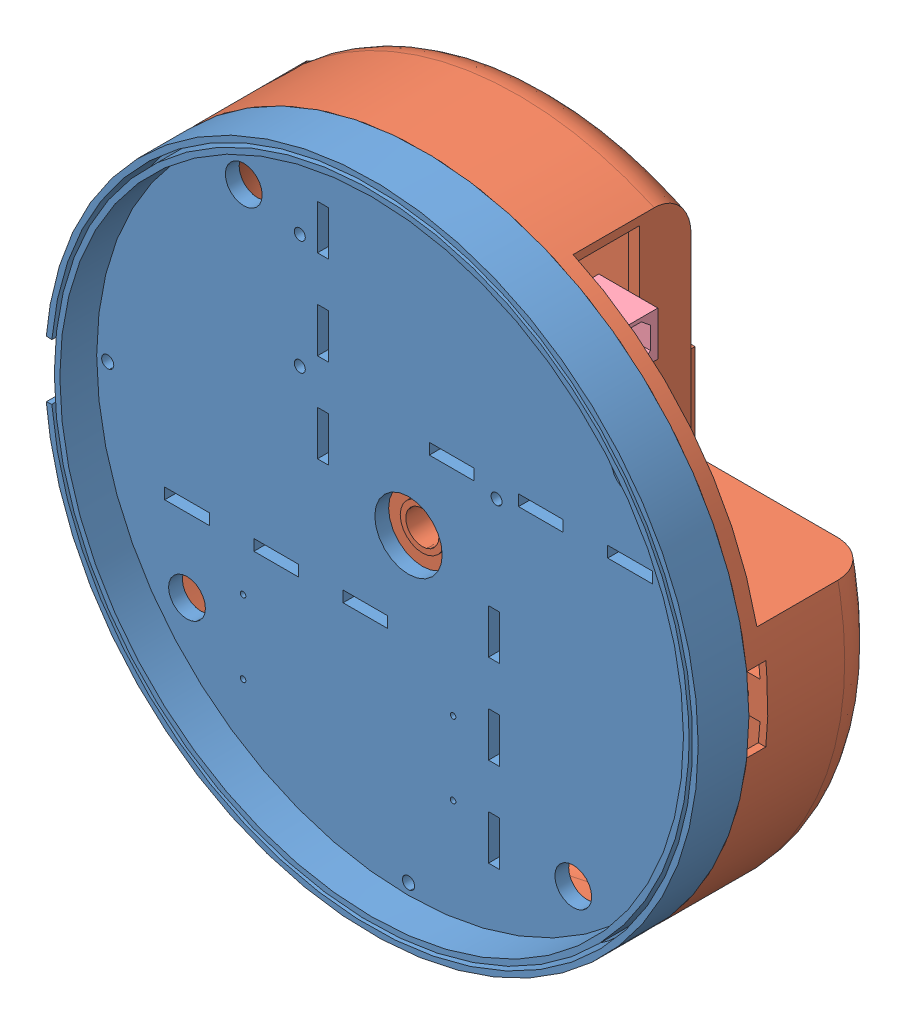
SolidWorks assembly MountAndBack, configuration Default. Lengths in mm.
Overall size (177.22 177.22 63.25).
4 component instances, 4 part files, 9 mates.
Components (placement in the parent):
- BackCover-1: BackCover [Default] at (59.4818 128.5471 115.0523) size (177.22 177.22 18.75)
- URVMount-1: URVMount [Default] at (59.4818 128.5471 111.3023) x (0 -1 0) z (0 0 1) size (177.22 177.22 49.5)
- ServoDriver-1: ServoDriver [Default] at (43.0849 82.2579 106.3023) x (0 0 1) z (-1 0 0) size (2 25 62.1)
- arduinoUnor-1: arduinoUnor [Default] at (54.6997 184.2196 96.9884) x (0 1 0) z (0 0 -1) size (54 75 15)
Mates (geometry in assembly coordinates):
- Concentric1: concentric aligned: cylinder of BackCover-1 through (59.4818 128.5471 111.3023) axis (0 0 1) radius 88.611; cylinder of URVMount-1 through (59.4818 128.5471 75.3023) axis (0 0 1) radius 88.611
- Coincident1: coincident anti-aligned: plane of BackCover-1 through (59.4818 128.5471 111.3023) normal (0 0 -1); plane of URVMount-1 through (59.4818 128.5471 111.3023) normal (0 0 1)
- Tangent1: tangent anti-aligned: face of BackHubDirect-1; plane of BackCover-1 through (83.3818 199.0471 106.3023) normal (0 0 -1)
- Tangent2: tangent anti-aligned: edge_curve of BackHubDirect-1; cylinder of BackCover-1 through (29.9818 153.5471 106.3023) axis (0 0 1) radius 1.5
- Tangent3: tangent anti-aligned: cylinder of BackCover-1 through (29.9818 184.5471 106.3023) axis (0 0 1) radius 1.5; edge_curve of arduinoUnor-1
- Coincident2: coincident anti-aligned: plane of BackCover-1 through (59.4818 128.5471 108.3023) normal (0 0 -1); plane of ServoDriverDirect-1 through (13.5349 93.2579 108.3023) normal (0 0 1)
- Concentric2: concentric anti-aligned: cylinder of BackCover-1 through (71.5742 72.3186 108.3023) axis (0 0 1) radius 0.75; cylinder of ServoDriverDirect-1 through (71.5742 72.3186 108.3023) axis (0 0 -1) radius 1
- Concentric3: concentric anti-aligned: cylinder of BackCover-1 through (71.5742 92.1972 108.3023) axis (0 0 1) radius 0.75; cylinder of ServoDriverDirect-1 through (71.5742 92.1972 108.3023) axis (0 0 -1) radius 1
- Parallel2: parallel: plane of BackCover-1 through (59.4818 103.8471 105.0523) normal (0 1 0); line of URVMount-1 through (59.4818 128.5471 111.3023) axis (-1 0 0)
